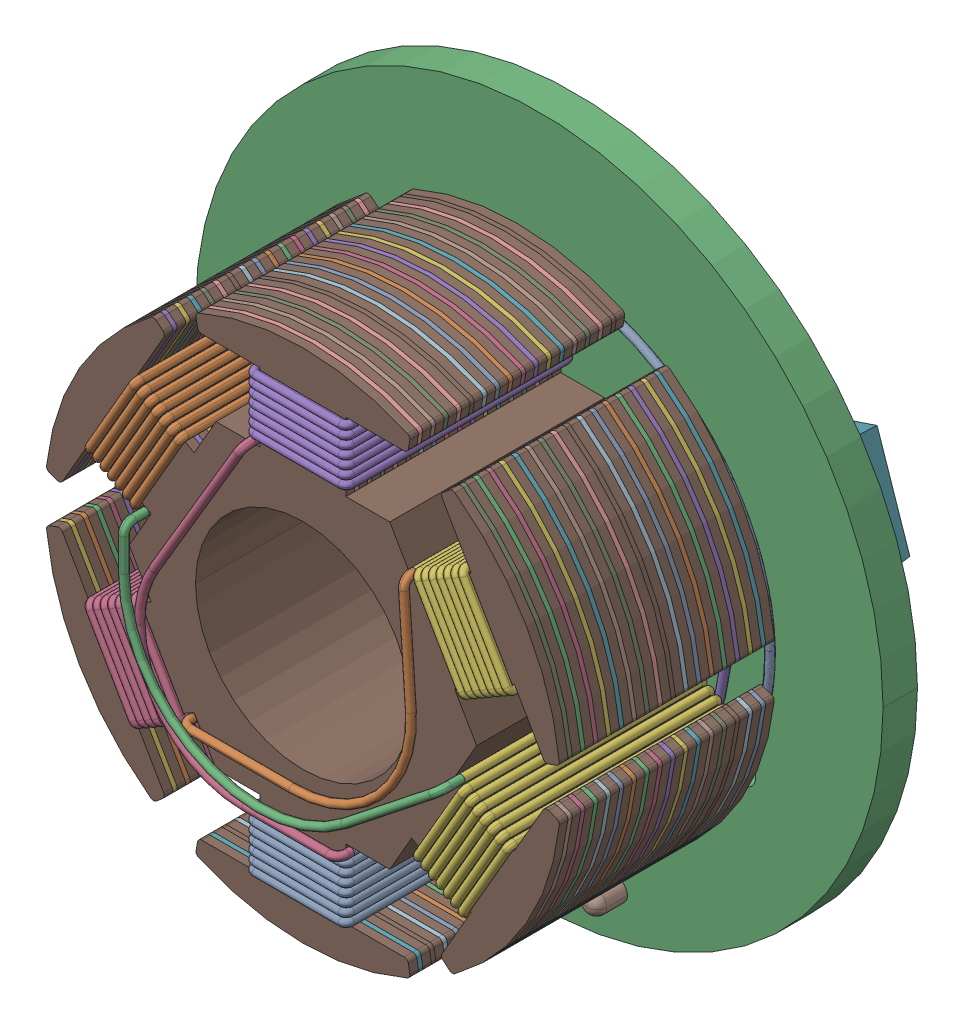
SolidWorks assembly Brushless motor, configuration 默认. Lengths in mm.
Overall size (16 16 8.48).
12 component instances, 7 part files, 0 mates.
Components (placement in the parent):
- Coil-1: Coil [默认] at (0 -5.01 1.29) x (-1 0 0) z (0 1 0) size (2.38 5.38 1.58)
- Coil-2: Coil [默认] at (-4.3388 2.505 1.29) x (0.5 0.866025 0) z (0.866025 -0.5 0) size (2.38 5.38 1.58)
- Board-1: Board [默认] at origin size (16 16 0.82)
- Coil-3: Coil [默认] at (-4.3388 -2.505 1.29) x (-0.5 0.866025 0) z (0.866025 0.5 0) size (2.38 5.38 1.58)
- Coil-4: Coil [默认] at (0 5.01 1.29) x (1 0 0) z (0 -1 0) size (2.38 5.38 1.58)
- Coil-5: Coil [默认] at (4.3388 2.505 1.29) x (0.5 -0.866025 0) z (-0.866025 -0.5 0) size (2.38 5.38 1.58)
- Hall Effect sensor_WE-1: Hall Effect sensor_WE [默认] at (-5.3023 -0.9391 0) x (-0.233503 0.972356 0) z (-0.972356 -0.233503 0) size (6.3 1.61 2.6)
- Pieza2_Brushless motor-1: Pieza2_Brushless motor [默认] at origin size (10.8 12.51 6.89)
- Coil-6: Coil [默认] at (4.3388 -2.505 1.29) x (-0.5 -0.866025 0) z (-0.866025 0.5 0) size (2.38 5.38 1.58)
- Controller-1: Controller [默认] at (5.1574 2.3195 0) x (0.319288 -0.947658 0) z (0.947658 0.319288 0) size (4.81 1 3)
- Pieza3_Brushless motor-1: Pieza3_Brushless motor [默认] at (0 0 0.8) size (4.11 0.74 1.7)
- Stator-1: Stator [默认] at (0 0 3.55) size (11.94 12.05 5.5)
